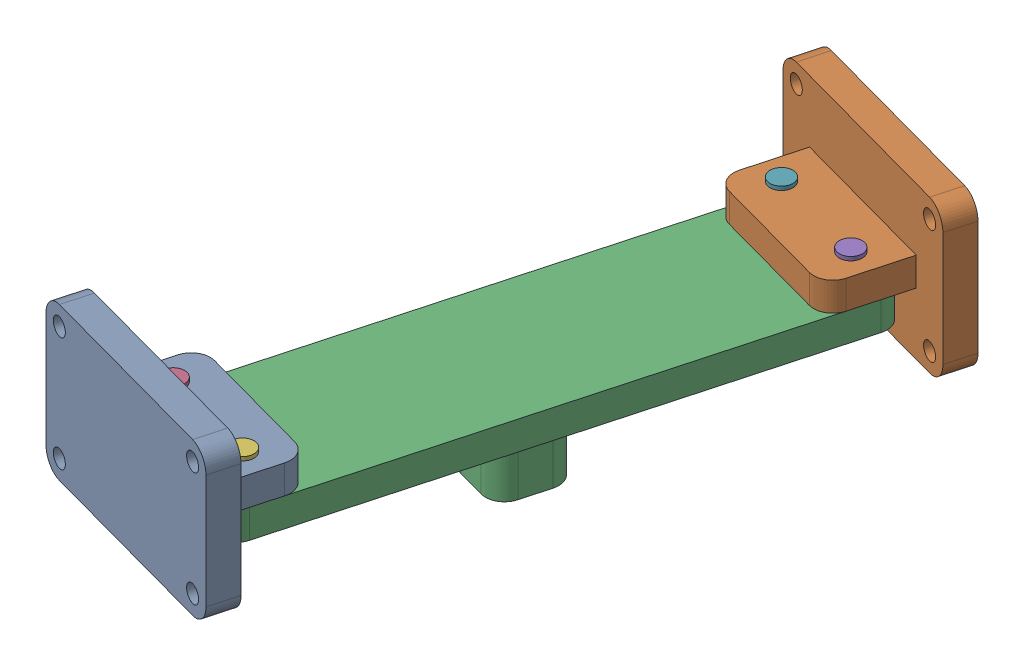
SolidWorks assembly Assem2, configuration Default. Lengths in mm.
Overall size (202.97 102.5 349.98).
6 component instances, 3 part files, 12 mates.
Components (placement in the parent):
- Part4-1: Part4 [Default] at (555.7311 944.5092 1326.4139) x (0.96442 0 0.264374) z (0 1 0) size (120 330 80)
- Part3-3: Part3 [Default] at (516.075 922.0092 1471.077) x (0.264374 0 -0.96442) z (0.96442 0 0.264374) size (290 55 80)
- pin2-5: pin2 [Default] at (456.6314 922.0092 1589.5779) size (12 34 12)
- pin2-6: pin2 [Default] at (575.5185 922.0092 1352.5761) size (12 34 12)
- pin2-7: pin2 [Default] at (506.7813 922.0092 1603.3253) size (12 34 12)
- pin2-8: pin2 [Default] at (525.3687 922.0723 1338.8286) size (12 34 12)
Mates (geometry in assembly coordinates):
- Coincident8: coincident anti-aligned: plane of Part4-1 through (583.7329 937.0092 1375.5657) normal (0 -1 0); plane of Part3-3 through (516.075 937.0092 1471.077) normal (0 1 0)
- Concentric15: concentric aligned: cylinder of Part4-1 through (575.5185 904.5092 1352.5761) axis (0 1 0) radius 4.5; cylinder of Part3-3 through (575.5185 922.0092 1352.5761) axis (0 1 0) radius 4.5
- Concentric16: concentric aligned: cylinder of Part4-1 through (525.3687 904.5092 1338.8286) axis (0 1 0) radius 4.5; cylinder of Part3-3 through (525.3687 922.0092 1338.8286) axis (0 1 0) radius 4.5
- Concentric17: concentric anti-aligned: cylinder of Part4-1 through (456.6314 984.5092 1589.5779) axis (0 -1 0) radius 4.5; cylinder of Part3-3 through (456.6314 922.0092 1589.5779) axis (0 1 0) radius 4.5
- Concentric18: concentric anti-aligned: cylinder of Part4-1 through (506.7813 984.5092 1603.3253) axis (0 -1 0) radius 4.5; cylinder of Part3-3 through (506.7813 922.0092 1603.3253) axis (0 1 0) radius 4.5
- Concentric23: concentric anti-aligned: cylinder of Part3-3 through (456.6314 922.0092 1589.5779) axis (0 1 0) radius 4.5; cylinder of pin2-5 through (456.6314 952.0092 1589.5779) axis (0 -1 0) radius 4.5
- Coincident19: coincident anti-aligned: plane of Part4-1 through (525.5706 952.0092 1587.7382) normal (0 1 0); plane of pin2-5 through (456.6314 952.0092 1589.5779) normal (0 -1 0)
- Concentric24: concentric anti-aligned: cylinder of Part3-3 through (525.3687 922.0092 1338.8286) axis (0 1 0) radius 4.5; cylinder of pin2-8 through (525.3687 952.0723 1338.8286) axis (0 -1 0) radius 4.5
- Concentric25: concentric anti-aligned: cylinder of Part3-3 through (575.5185 922.0092 1352.5761) axis (0 1 0) radius 4.5; cylinder of pin2-6 through (575.5185 952.0092 1352.5761) axis (0 -1 0) radius 4.5
- Coincident20: coincident anti-aligned: plane of Part4-1 through (583.7329 952.0092 1375.5657) normal (0 1 0); plane of pin2-6 through (575.5185 952.0092 1352.5761) normal (0 -1 0)
- Concentric26: concentric anti-aligned: cylinder of Part3-3 through (506.7813 922.0092 1603.3253) axis (0 1 0) radius 4.5; cylinder of pin2-7 through (506.7813 952.0092 1603.3253) axis (0 -1 0) radius 4.5
- Coincident21: coincident anti-aligned: plane of Part4-1 through (525.5706 952.0092 1587.7382) normal (0 1 0); plane of pin2-7 through (506.7813 952.0092 1603.3253) normal (0 -1 0)
